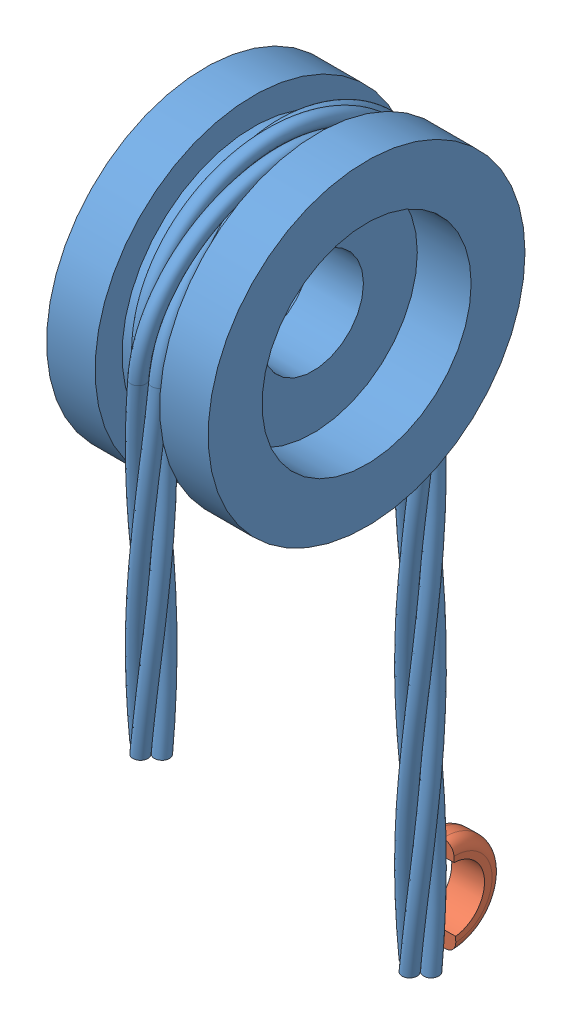
SolidWorks assembly Pully, configuration Default. Lengths in mm.
Overall size (3.81 18.98 8.49).
2 component instances, 2 part files, 1 mates.
Components (placement in the parent):
- Pulley for Recycling-1: Pulley for Recycling [Default] at (4.5635 15.5704 12.0455) size (3.81 18.98 7.47)
- Hook (2)-1: Hook (2) [Default] at (4.2001 1.6207 8.4944) x (0.000217 -0.999714 -0.023913) z (0.999915 0.000529 -0.013043) size (2.29 1.14 0.76)
Mates (geometry in assembly coordinates):
- Tangent1: tangent: plane of assembly; face of Pulley for Recycling-1; plane of Hook (2)-1 through (4.962 1.6211 8.4845) normal (0.013051 -0.023908 0.999629)
